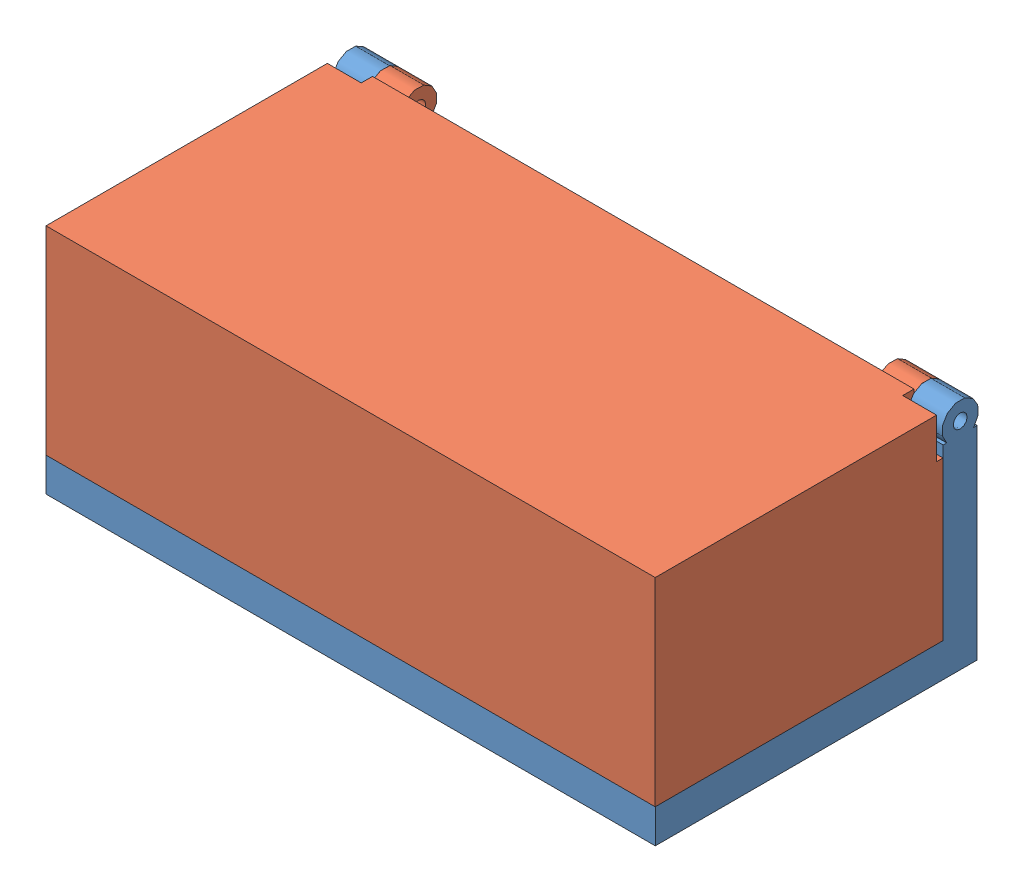
SolidWorks assembly box assembly, configuration Default. Lengths in mm.
Overall size (269.8 103.77 143.37).
2 component instances, 2 part files, 1 mates.
Components (placement in the parent):
- Bot Bottom-1: Bot Bottom [Default] at (125.4878 62.0034 237.3922) size (269.8 103.54 143.35)
- Box Top-2: Box Top [Default] at (78.871 81.3862 256.775) x (-1 0 0) z (0 -1 0) size (269.8 143.14 88.8)
Mates (geometry in assembly coordinates):
- Coincident1: coincident aligned: circle of Bot Bottom-1; circle of Box Top-2
